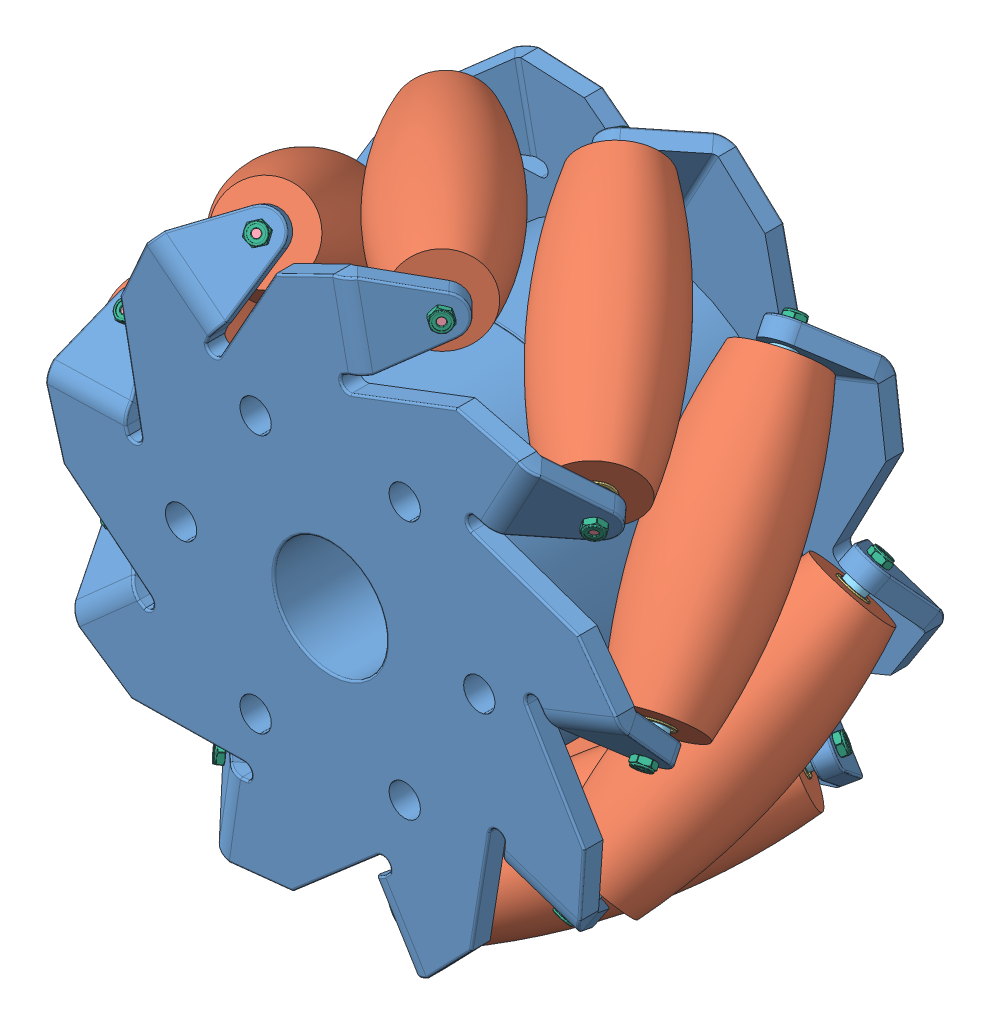
SolidWorks assembly Mecanum, configuration Default. Lengths in mm.
Overall size (786.27 905.13 778.69).
83 component instances, 6 part files, 34 mates.
Components (placement in the parent):
- plate_new-1: plate_new [Default] at (266.3524 358.6444 438.1362) size (91.48 92.19 26.23)
- plate_new-3: plate_new [Default] at (266.3 358.4865 490.0162) x (0.801436 -0.598081 0) z (0 0 -1) size (91.48 92.19 26.23)
- satellitewheel_assembly_2-2: satellitewheel_assembly_2 [Default] at (240.34 156.2975 637.1835) x (0.110588 -0.759454 0.641092) z (-0.875831 -0.379368 -0.29833) size (550.8 76.63 18.72)
  - Satellite Wheel-1: Satellite Wheel [Default] at (-230.7088 -10.4586 -3.6611) size (550.8 71.36 18.72)
  - instrument ball bearing_68_am-1: instrument ball bearing_68_am [AFBMA 12.1.4.1 - 0015-5 - 8,SI,NC,8_68] at (-249.7985 1.4263 -3.6611) x (0 1 0) z (0.469874 0 0.882734) size (2 5 5)
  - instrument ball bearing_68_am-3: instrument ball bearing_68_am [AFBMA 12.1.4.1 - 0015-5 - 8,SI,NC,8_68] at (-249.7985 -41.1817 -3.6611) x (0 -1 0) z (0.579803 0 0.814757) size (2 5 5)
  - wheelshaft-1: wheelshaft [Default] at (-249.7985 1.7223 -3.6611) x (-0.300283 0 0.95385) z (0 -1 0) size (2.35 2.35 54.72)
- satellitewheel_assembly_2-3: satellitewheel_assembly_2 [Default] at (283.3422 206.5509 649.0028) x (0.287219 -0.673344 0.681259) z (-0.957653 -0.216829 0.189438) size (550.8 76.63 18.72)
  - Satellite Wheel-1: Satellite Wheel [Default] at (-230.7088 -10.4586 -3.6611) size (550.8 71.36 18.72)
  - instrument ball bearing_68_am-1: instrument ball bearing_68_am [AFBMA 12.1.4.1 - 0015-5 - 8,SI,NC,8_68] at (-249.7985 1.4263 -3.6611) x (0 1 0) z (0.469874 0 0.882734) size (2 5 5)
  - instrument ball bearing_68_am-3: instrument ball bearing_68_am [AFBMA 12.1.4.1 - 0015-5 - 8,SI,NC,8_68] at (-249.7985 -41.1817 -3.6611) x (0 -1 0) z (0.579803 0 0.814757) size (2 5 5)
  - wheelshaft-1: wheelshaft [Default] at (-249.7985 1.7223 -3.6611) x (-0.300283 0 0.95385) z (0 -1 0) size (2.35 2.35 54.72)
- satellitewheel_assembly_2-5: satellitewheel_assembly_2 [Default] at (361.8848 197.9619 554.4207) x (0.528345 -0.795765 0.29599) z (-0.726791 -0.243689 0.642176) size (550.8 76.63 18.72)
  - Satellite Wheel-1: Satellite Wheel [Default] at (-230.7088 -10.4586 -3.6611) size (550.8 71.36 18.72)
  - instrument ball bearing_68_am-1: instrument ball bearing_68_am [AFBMA 12.1.4.1 - 0015-5 - 8,SI,NC,8_68] at (-249.7985 1.4263 -3.6611) x (0 1 0) z (0.469874 0 0.882734) size (2 5 5)
  - instrument ball bearing_68_am-3: instrument ball bearing_68_am [AFBMA 12.1.4.1 - 0015-5 - 8,SI,NC,8_68] at (-249.7985 -41.1817 -3.6611) x (0 -1 0) z (0.579803 0 0.814757) size (2 5 5)
  - wheelshaft-1: wheelshaft [Default] at (-249.7985 1.7223 -3.6611) x (-0.300283 0 0.95385) z (0 -1 0) size (2.35 2.35 54.72)
- satellitewheel_assembly_2-7: satellitewheel_assembly_2 [Default] at (377.9353 566.3135 329.894) x (0.463445 0.663225 -0.587666) z (0.552767 -0.734711 -0.393254) size (550.8 76.63 18.72)
  - Satellite Wheel-1: Satellite Wheel [Default] at (-230.7088 -10.4586 -3.6611) size (550.8 71.36 18.72)
  - instrument ball bearing_68_am-1: instrument ball bearing_68_am [AFBMA 12.1.4.1 - 0015-5 - 8,SI,NC,8_68] at (-249.7985 1.4263 -3.6611) x (0 1 0) z (0.469874 0 0.882734) size (2 5 5)
  - instrument ball bearing_68_am-3: instrument ball bearing_68_am [AFBMA 12.1.4.1 - 0015-5 - 8,SI,NC,8_68] at (-249.7985 -41.1817 -3.6611) x (0 -1 0) z (0.579803 0 0.814757) size (2 5 5)
  - wheelshaft-1: wheelshaft [Default] at (-249.7985 1.7223 -3.6611) x (-0.300283 0 0.95385) z (0 -1 0) size (2.35 2.35 54.72)
- satellitewheel_assembly_2-9: satellitewheel_assembly_2 [Default] at (133.5045 195.5106 518.9885) x (-0.598803 -0.78606 0.153442) z (-0.50428 0.51889 0.690258) size (550.8 76.63 18.72)
  - Satellite Wheel-1: Satellite Wheel [Default] at (-230.7088 -10.4586 -3.6611) size (550.8 71.36 18.72)
  - instrument ball bearing_68_am-1: instrument ball bearing_68_am [AFBMA 12.1.4.1 - 0015-5 - 8,SI,NC,8_68] at (-249.7985 1.4263 -3.6611) x (0 1 0) z (0.469874 0 0.882734) size (2 5 5)
  - instrument ball bearing_68_am-3: instrument ball bearing_68_am [AFBMA 12.1.4.1 - 0015-5 - 8,SI,NC,8_68] at (-249.7985 -41.1817 -3.6611) x (0 -1 0) z (0.579803 0 0.814757) size (2 5 5)
  - wheelshaft-1: wheelshaft [Default] at (-249.7985 1.7223 -3.6611) x (-0.300283 0 0.95385) z (0 -1 0) size (2.35 2.35 54.72)
- satellitewheel_assembly_2-11: satellitewheel_assembly_2 [Default] at (484.0302 512.4486 546.743) x (0.74644 0.601733 0.284156) z (0.612265 -0.453736 -0.647499) size (550.8 76.63 18.72)
  - Satellite Wheel-1: Satellite Wheel [Default] at (-230.7088 -10.4586 -3.6611) size (550.8 71.36 18.72)
  - instrument ball bearing_68_am-1: instrument ball bearing_68_am [AFBMA 12.1.4.1 - 0015-5 - 8,SI,NC,8_68] at (-249.7985 1.4263 -3.6611) x (0 1 0) z (0.469874 0 0.882734) size (2 5 5)
  - instrument ball bearing_68_am-3: instrument ball bearing_68_am [AFBMA 12.1.4.1 - 0015-5 - 8,SI,NC,8_68] at (-249.7985 -41.1817 -3.6611) x (0 -1 0) z (0.579803 0 0.814757) size (2 5 5)
  - wheelshaft-1: wheelshaft [Default] at (-249.7985 1.7223 -3.6611) x (-0.300283 0 0.95385) z (0 -1 0) size (2.35 2.35 54.72)
- satellitewheel_assembly_2-13: satellitewheel_assembly_2 [Default] at (136.2637 218.061 317.8586) x (-0.589947 -0.48463 -0.64583) z (-0.776094 0.561048 0.28793) size (550.8 76.63 18.72)
  - Satellite Wheel-1: Satellite Wheel [Default] at (-230.7088 -10.4586 -3.6611) size (550.8 71.36 18.72)
  - instrument ball bearing_68_am-1: instrument ball bearing_68_am [AFBMA 12.1.4.1 - 0015-5 - 8,SI,NC,8_68] at (-249.7985 1.4263 -3.6611) x (0 1 0) z (0.469874 0 0.882734) size (2 5 5)
  - instrument ball bearing_68_am-3: instrument ball bearing_68_am [AFBMA 12.1.4.1 - 0015-5 - 8,SI,NC,8_68] at (-249.7985 -41.1817 -3.6611) x (0 -1 0) z (0.579803 0 0.814757) size (2 5 5)
  - wheelshaft-1: wheelshaft [Default] at (-249.7985 1.7223 -3.6611) x (-0.300283 0 0.95385) z (0 -1 0) size (2.35 2.35 54.72)
- satellitewheel_assembly_2-15: satellitewheel_assembly_2 [Default] at (405.8054 118.1885 493.0949) x (0.581675 -0.810385 0.070213) z (-0.546989 -0.453578 -0.703612) size (550.8 76.63 18.72)
  - Satellite Wheel-1: Satellite Wheel [Default] at (-230.7088 -10.4586 -3.6611) size (550.8 71.36 18.72)
  - instrument ball bearing_68_am-1: instrument ball bearing_68_am [AFBMA 12.1.4.1 - 0015-5 - 8,SI,NC,8_68] at (-249.7985 1.4263 -3.6611) x (0 1 0) z (0.469874 0 0.882734) size (2 5 5)
  - instrument ball bearing_68_am-3: instrument ball bearing_68_am [AFBMA 12.1.4.1 - 0015-5 - 8,SI,NC,8_68] at (-249.7985 -41.1817 -3.6611) x (0 -1 0) z (0.579803 0 0.814757) size (2 5 5)
  - wheelshaft-1: wheelshaft [Default] at (-249.7985 1.7223 -3.6611) x (-0.300283 0 0.95385) z (0 -1 0) size (2.35 2.35 54.72)
- satellitewheel_assembly_2-17: satellitewheel_assembly_2 [Default] at (393.4095 235.7199 648.3967) x (0.640227 -0.34921 0.684224) z (-0.317325 -0.931379 -0.178431) size (550.8 76.63 18.72)
  - Satellite Wheel-1: Satellite Wheel [Default] at (-230.7088 -10.4586 -3.6611) size (550.8 71.36 18.72)
  - instrument ball bearing_68_am-1: instrument ball bearing_68_am [AFBMA 12.1.4.1 - 0015-5 - 8,SI,NC,8_68] at (-249.7985 1.4263 -3.6611) x (0 1 0) z (0.469874 0 0.882734) size (2 5 5)
  - instrument ball bearing_68_am-3: instrument ball bearing_68_am [AFBMA 12.1.4.1 - 0015-5 - 8,SI,NC,8_68] at (-249.7985 -41.1817 -3.6611) x (0 -1 0) z (0.579803 0 0.814757) size (2 5 5)
  - wheelshaft-1: wheelshaft [Default] at (-249.7985 1.7223 -3.6611) x (-0.300283 0 0.95385) z (0 -1 0) size (2.35 2.35 54.72)
- spacer-1: spacer [Default] at (296.094 366.0453 447.5978) x (0.970921 -0.087587 0.222803) z (-0.222803 -0.671088 0.707107) size (3.5 3.5 1)
- spacer-10: spacer [Default] at (232.2466 326.7143 480.5546) x (0.272456 0.953228 0.130861) z (0.699582 -0.102885 -0.707107) size (3.5 3.5 1)
- spacer-2: spacer [Default] at (284.0721 392.1809 447.5978) x (0.800068 0.557 0.222803) z (0.26069 -0.657298 0.707107) size (3.5 3.5 1)
- spacer-3: spacer [Default] at (258.0631 404.4744 447.5978) x (0.254855 0.940961 0.222803) z (0.622203 -0.335951 0.707107) size (3.5 3.5 1)
- spacer-4: spacer [Default] at (230.237 397.1735 447.5978) x (-0.409608 0.884636 0.222803) z (0.692581 0.142591 0.707107) size (3.5 3.5 1)
- spacer-5: spacer [Default] at (213.6139 373.6945 447.5978) x (-0.882411 0.414379 0.222803) z (0.438892 0.554413 0.707107) size (3.5 3.5 1)
- spacer-6: spacer [Default] at (215.9719 345.0233 447.5978) x (-0.942324 -0.24977 0.222803) z (-0.020159 0.706819 0.707107) size (3.5 3.5 1)
- spacer-7: spacer [Default] at (236.2076 324.5756 447.5978) x (-0.561313 -0.797049 0.222803) z (-0.469778 0.528497 0.707107) size (3.5 3.5 1)
- spacer-8: spacer [Default] at (264.8527 321.9191 447.5978) x (0.082342 -0.97138 0.222803) z (-0.699582 0.102885 0.707107) size (3.5 3.5 1)
- spacer-9: spacer [Default] at (288.5036 338.2968 447.5978) x (0.687469 -0.691191 0.222803) z (-0.602044 -0.370868 0.707107) size (3.5 3.5 1)
- spacer-12: spacer [Default] at (260.4436 321.0113 480.5546) x (-0.40401 0.905346 0.130861) z (0.602044 0.370868 -0.707107) size (3.5 3.5 1)
- spacer-13: spacer [Default] at (285.7096 334.7673 480.5546) x (-0.891435 0.433843 0.130861) z (0.222803 0.671088 -0.707107) size (3.5 3.5 1)
- spacer-14: spacer [Default] at (296.2223 361.5456 480.5546) x (-0.961747 -0.240661 0.130861) z (-0.26069 0.657298 -0.707107) size (3.5 3.5 1)
- spacer-15: spacer [Default] at (287.0628 388.8164 480.5546) x (-0.582048 -0.802556 0.130861) z (-0.622203 0.335951 -0.707107) size (3.5 3.5 1)
- spacer-16: spacer [Default] at (262.5168 403.8194 480.5546) x (0.069999 -0.988927 0.130861) z (-0.692581 -0.142591 -0.707107) size (3.5 3.5 1)
- spacer-17: spacer [Default] at (234.0697 399.5346 480.5546) x (0.689292 -0.712567 0.130861) z (-0.438892 -0.554413 -0.707107) size (3.5 3.5 1)
- spacer-18: spacer [Default] at (215.0323 377.9667 480.5546) x (0.986058 -0.10279 0.130861) z (0.020159 -0.706819 -0.707107) size (3.5 3.5 1)
- spacer-19: spacer [Default] at (214.3122 349.2078 480.5546) x (0.821436 0.555084 0.130861) z (0.469778 -0.528497 -0.707107) size (3.5 3.5 1)
- locknut-1: locknut [Default] at (297.0124 359.5533 482.6979) x (0.96019 0.100375 -0.26069) z (0.26069 -0.657298 0.707107) size (2.95 3.35 1.34)
- locknut-10: locknut [Default] at (290.3284 339.4208 445.4546) x (-0.643198 0.749999 -0.154265) z (0.602044 0.370868 -0.707107) size (2.95 3.35 1.34)
- locknut-2: locknut [Default] at (288.9486 387.7981 482.6979) x (0.671029 0.69409 -0.26069) z (0.622203 -0.335951 0.707107) size (2.95 3.35 1.34)
- locknut-3: locknut [Default] at (264.616 404.2516 482.6979) x (0.067885 0.963033 -0.26069) z (0.692581 0.142591 0.707107) size (2.95 3.35 1.34)
- locknut-4: locknut [Default] at (235.4 401.215 482.6979) x (-0.567023 0.781362 -0.26069) z (0.438892 0.554413 0.707107) size (2.95 3.35 1.34)
- locknut-5: locknut [Default] at (214.9712 380.1091 482.6979) x (-0.936614 0.234083 -0.26069) z (-0.020159 0.706819 0.707107) size (2.95 3.35 1.34)
- locknut-6: locknut [Default] at (212.8884 350.8096 482.6979) x (-0.867953 -0.422726 -0.26069) z (-0.469778 0.528497 0.707107) size (2.95 3.35 1.34)
- locknut-7: locknut [Default] at (230.1262 327.0262 482.6979) x (-0.393168 -0.881737 -0.26069) z (-0.699582 0.102885 0.707107) size (2.95 3.35 1.34)
- locknut-8: locknut [Default] at (258.6188 319.8872 482.6979) x (0.265586 -0.928173 -0.26069) z (-0.602044 -0.370868 0.707107) size (2.95 3.35 1.34)
- locknut-9: locknut [Default] at (285.0343 332.7332 482.6979) x (0.800068 -0.540307 -0.26069) z (-0.222803 -0.671088 0.707107) size (2.95 3.35 1.34)
- locknut-20: locknut [Default] at (266.9731 321.6072 445.4546) x (-0.010628 0.987972 -0.154265) z (0.699582 -0.102885 -0.707107) size (2.95 3.35 1.34)
- locknut-21: locknut [Default] at (237.6315 322.9737 445.4546) x (0.626915 0.763662 -0.154265) z (0.469778 -0.528497 -0.707107) size (2.95 3.35 1.34)
- locknut-22: locknut [Default] at (216.033 342.8809 445.4546) x (0.971117 0.182026 -0.154265) z (0.020159 -0.706819 -0.707107) size (2.95 3.35 1.34)
- locknut-23: locknut [Default] at (212.2836 372.014 445.4546) x (0.860923 -0.484782 -0.154265) z (-0.438892 -0.554413 -0.707107) size (2.95 3.35 1.34)
- locknut-24: locknut [Default] at (228.1378 396.7413 445.4546) x (0.347893 -0.924755 -0.154265) z (-0.692581 -0.142591 -0.707107) size (2.95 3.35 1.34)
- locknut-25: locknut [Default] at (256.1772 405.4927 445.4546) x (-0.32792 -0.932025 -0.154265) z (-0.622203 0.335951 -0.707107) size (2.95 3.35 1.34)
- locknut-26: locknut [Default] at (283.2819 394.1732 445.4546) x (-0.850295 -0.50319 -0.154265) z (-0.26069 0.657298 -0.707107) size (2.95 3.35 1.34)
- locknut-27: locknut [Default] at (296.7693 368.0794 445.4546) x (-0.974808 0.161093 -0.154265) z (0.222803 0.671088 -0.707107) size (2.95 3.35 1.34)
Mates (geometry in assembly coordinates):
- Concentric1: concentric anti-aligned: cylinder of plate_new-1 through (254.1795 362.5982 487.1362) axis (0 0 -1) radius 26.645; cylinder of plate_new-3 through (254.1795 362.5982 441.0162) axis (0 0 1) radius 26.645
- Parallel3: parallel anti-aligned: plane of plate_new-1 through (296.1661 366.2627 447.783) normal (-0.222803 -0.671088 0.707107); plane of plate_new-3 through (285.6374 334.5499 480.3694) normal (0.222803 0.671088 -0.707107)
- Width1: width anti-aligned: plane of plate_new-1 through (227.9349 396.6996 445.6617) normal (-0.692581 -0.142591 -0.707107); plane of plate_new-3 through (264.8188 404.2934 482.4908) normal (0.692581 0.142591 0.707107); plane of satellitewheel_assembly_2-2/Satellite Wheel-1 through (216.867 334.9383 491.2002) normal (-0.469778 0.528497 0.707107); plane of satellitewheel_assembly_2-2/Satellite Wheel-1 through (237.6218 311.5893 459.9602) normal (0.469778 -0.528497 -0.707107)
- Concentric2: concentric anti-aligned: circle of plate_new-1; circle of satellitewheel_assembly_2-2/Satellite Wheel-1
- Width2: width anti-aligned: plane of satellitewheel_assembly_2-2/Satellite Wheel-1 through (237.6218 311.5893 459.9602) normal (0.469778 -0.528497 -0.707107); plane of satellitewheel_assembly_2-2/Satellite Wheel-1 through (216.867 334.9383 491.2002) normal (-0.469778 0.528497 0.707107); plane of plate_new-3 through (212.7508 350.9644 482.4908) normal (-0.469778 0.528497 0.707107); plane of plate_new-1 through (237.7691 322.819 445.6617) normal (0.469778 -0.528497 -0.707107)
- Concentric3: concentric aligned: circle of plate_new-3; circle of satellitewheel_assembly_2-2/wheelshaft-1
- Concentric4: concentric anti-aligned: circle of plate_new-1; circle of satellitewheel_assembly_2-3/Satellite Wheel-1
- Width3: width anti-aligned: plane of satellitewheel_assembly_2-3/Satellite Wheel-1 through (221.1013 333.7987 460.6809) normal (0.020159 -0.706819 -0.707107); plane of satellitewheel_assembly_2-3/Satellite Wheel-1 through (220.2107 365.026 491.9209) normal (-0.020159 0.706819 0.707107); plane of plate_new-1 through (216.0389 342.6739 445.6617) normal (0.020159 -0.706819 -0.707107); plane of plate_new-3 through (214.9652 380.3161 482.4908) normal (-0.020159 0.706819 0.707107)
- Concentric5: concentric aligned: circle of plate_new-3; circle of satellitewheel_assembly_2-3/wheelshaft-1
- Concentric6: concentric anti-aligned: circle of plate_new-1; circle of satellitewheel_assembly_2-5/Satellite Wheel-1
- Width4: width anti-aligned: plane of satellitewheel_assembly_2-5/Satellite Wheel-1 through (223.6274 360.0881 453.7676) normal (-0.438892 -0.554413 -0.707107); plane of satellitewheel_assembly_2-5/Satellite Wheel-1 through (243.0177 384.5821 485.0075) normal (0.438892 0.554413 0.707107); plane of plate_new-3 through (235.5285 401.3773 482.4908) normal (0.438892 0.554413 0.707107); plane of plate_new-1 through (212.155 371.8517 445.6617) normal (-0.438892 -0.554413 -0.707107)
- Concentric7: concentric aligned: circle of plate_new-3; circle of satellitewheel_assembly_2-5/wheelshaft-1
- Concentric8: concentric anti-aligned: circle of plate_new-1; circle of satellitewheel_assembly_2-7/Satellite Wheel-1
- Width5: width anti-aligned: plane of satellitewheel_assembly_2-7/Satellite Wheel-1 through (239.394 409.2477 437.911) normal (-0.692581 -0.142591 -0.707107); plane of satellitewheel_assembly_2-7/Satellite Wheel-1 through (269.9922 415.5474 469.151) normal (0.692581 0.142591 0.707107); plane of plate_new-3 through (264.8188 404.2934 482.4908) normal (0.692581 0.142591 0.707107); plane of plate_new-1 through (227.9349 396.6996 445.6617) normal (-0.692581 -0.142591 -0.707107)
- Concentric9: concentric aligned: circle of plate_new-3; circle of satellitewheel_assembly_2-7/wheelshaft-1
- Concentric10: concentric anti-aligned: circle of plate_new-1; circle of satellitewheel_assembly_2-9/Satellite Wheel-1
- Width6: width anti-aligned: plane of satellitewheel_assembly_2-9/Satellite Wheel-1 through (248.0734 389.9613 451.2096) normal (-0.622203 0.335951 -0.707107); plane of satellitewheel_assembly_2-9/Satellite Wheel-1 through (275.5623 375.1189 482.4496) normal (0.622203 -0.335951 0.707107); plane of plate_new-3 through (289.1309 387.6997 482.4908) normal (0.622203 -0.335951 0.707107); plane of plate_new-1 through (255.995 405.5911 445.6617) normal (-0.622203 0.335951 -0.707107)
- Concentric11: concentric aligned: circle of plate_new-3; circle of satellitewheel_assembly_2-9/wheelshaft-1
- Concentric12: concentric anti-aligned: circle of plate_new-1; circle of satellitewheel_assembly_2-11/Satellite Wheel-1
- Width8: width anti-aligned: plane of satellitewheel_assembly_2-11/Satellite Wheel-1 through (297.7829 402.1806 453.5552) normal (-0.26069 0.657298 -0.707107); plane of satellitewheel_assembly_2-11/Satellite Wheel-1 through (309.3002 373.1412 484.7952) normal (0.26069 -0.657298 0.707107); plane of plate_new-3 through (297.0888 359.3608 482.4908) normal (0.26069 -0.657298 0.707107); plane of plate_new-1 through (283.2056 394.3657 445.6617) normal (-0.26069 0.657298 -0.707107)
- Concentric13: concentric aligned: circle of plate_new-3; circle of satellitewheel_assembly_2-11/wheelshaft-1
- Concentric14: concentric anti-aligned: circle of plate_new-1; circle of satellitewheel_assembly_2-13/Satellite Wheel-1
- Width9: width anti-aligned: plane of satellitewheel_assembly_2-13/Satellite Wheel-1 through (285.2373 356.5343 436.8673) normal (0.222803 0.671088 -0.707107); plane of satellitewheel_assembly_2-13/Satellite Wheel-1 through (275.3939 326.8856 468.1072) normal (-0.222803 -0.671088 0.707107); plane of plate_new-3 through (284.969 332.5366 482.4908) normal (-0.222803 -0.671088 0.707107); plane of plate_new-1 through (296.8345 368.2759 445.6617) normal (0.222803 0.671088 -0.707107)
- Concentric15: concentric aligned: circle of plate_new-3; circle of satellitewheel_assembly_2-13/wheelshaft-1
- Concentric16: concentric anti-aligned: circle of plate_new-1; circle of satellitewheel_assembly_2-15/Satellite Wheel-1
- Width10: width anti-aligned: plane of satellitewheel_assembly_2-15/Satellite Wheel-1 through (298.2105 323.3047 449.7162) normal (0.602044 0.370868 -0.707107); plane of satellitewheel_assembly_2-15/Satellite Wheel-1 through (271.6122 306.9198 480.9561) normal (-0.602044 -0.370868 0.707107); plane of plate_new-3 through (258.4425 319.7786 482.4908) normal (-0.602044 -0.370868 0.707107); plane of plate_new-1 through (290.5048 339.5295 445.6617) normal (0.602044 0.370868 -0.707107)
- Concentric17: concentric aligned: circle of plate_new-3; circle of satellitewheel_assembly_2-15/wheelshaft-1
- Concentric18: concentric anti-aligned: circle of plate_new-1; circle of satellitewheel_assembly_2-17/Satellite Wheel-1
- Width11: width anti-aligned: plane of satellitewheel_assembly_2-17/Satellite Wheel-1 through (275.4918 315.7777 460.7342) normal (0.699582 -0.102885 -0.707107); plane of satellitewheel_assembly_2-17/Satellite Wheel-1 through (244.5843 320.3231 491.9741) normal (-0.699582 0.102885 0.707107); plane of plate_new-3 through (229.9213 327.0563 482.4908) normal (-0.699582 0.102885 0.707107); plane of plate_new-1 through (267.178 321.5771 445.6617) normal (0.699582 -0.102885 -0.707107)
- Concentric19: concentric aligned: circle of plate_new-3; circle of satellitewheel_assembly_2-17/wheelshaft-1
- ProfileCenter1: profile center anti-aligned: plane of spacer-1 through (295.8712 365.3742 448.3049) normal (-0.222803 -0.671088 0.707107); plane of satellitewheel_assembly_2-13/instrument ball bearing_68_am-3 through (295.7991 363.6819 446.676) normal (0.222803 0.671088 -0.707107)
- ProfileCenter2: profile center anti-aligned: plane of spacer-10 through (232.9462 326.6115 479.8475) normal (0.699582 -0.102885 -0.707107); plane of satellitewheel_assembly_2-17/instrument ball bearing_68_am-1 through (232.3033 326.495 479.2285) normal (-0.699582 0.102885 0.707107)
- ProfileCenter3: profile center aligned: plane of locknut-1 through (297.0124 359.5533 482.6979) normal (-0.26069 0.657298 -0.707107); circle of plate_new-3
- ProfileCenter4: profile center aligned: plane of locknut-10 through (290.3284 339.4208 445.4546) normal (-0.602044 -0.370868 0.707107); circle of plate_new-1
